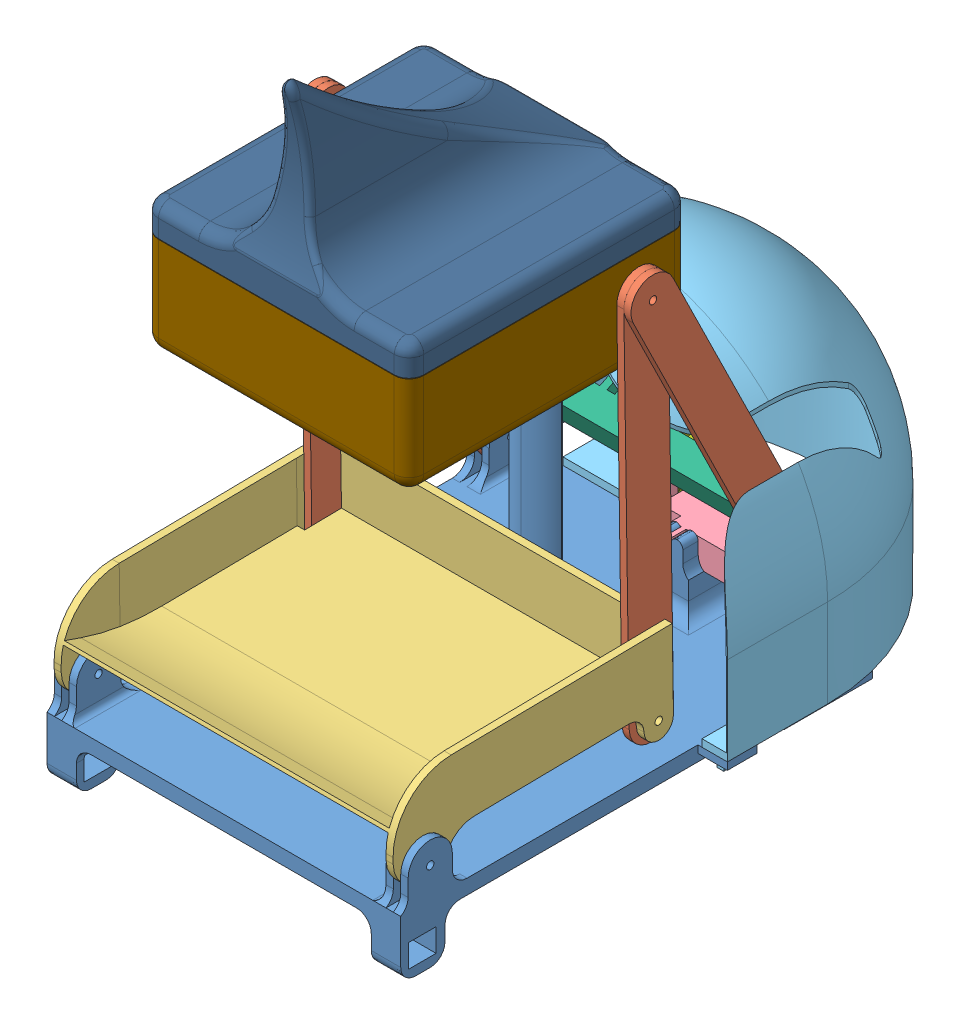
SolidWorks assembly Assembly, configuration Default. Lengths in mm.
Overall size (177.8 285.2 260.6).
13 component instances, 10 part files, 37 mates.
Components (placement in the parent):
- Base-1: Base [Default] at origin size (177.8 177.8 230.14)
- LinkGround-1: LinkGround [Follower] at (149.098 19.05 12.7) x (0 0.897199 0.441627) z (-1 0 0) size (196.85 19.05 3.05)
- ExtendedCrank-1: ExtendedCrank [Default] at (149.225 28.5357 89.033) x (-1 0 0) z (0 -0.015264 0.999884) size (146.05 40.64 120.65)
- LinkGround-3: LinkGround [Top] at (6.35 20.6008 88.9118) x (0 0.999893 0.014618) z (1 0 0) size (177.04 19.05 3.05)
- LinkGround-4: LinkGround [Top] at (143.002 178.5719 91.2213) x (0 -0.999893 -0.014618) z (1 0 0) size (177.04 19.05 3.05)
- LinkGround-8: LinkGround [Follower] at (6.35 19.05 12.7) x (0 0.897199 0.441627) z (-1 0 0) size (196.85 19.05 3.05)
- ServoMock-1: ServoMock [Default] at (115.57 32.4287 -6.1468) x (0 0 1) z (0 -1 0) size (42.32 37.85 19.81)
- Part2-1: Part2 [Default] at (0 6.35 0) x (1 0 0) z (0 1 0) size (177.8 139.57 134.62)
- NewServoHinge-1: NewServoHinge [Default] at (76.2 75.4719 46.7291) x (0 0.441627 -0.897199) z (1 0 0) size (30.48 12.7 145.8)
- ServoMountWheel-1: ServoMountWheel [Default] at (77.724 41.0778 -1.0841) x (0 -0.463784 0.885949) z (-1 0 0) size (50.53 31.75 8.57)
- LinkServo-1: LinkServo [Default] at (74.5236 47.7816 -6.8208) x (0 0.76136 0.64833) z (0 0.64833 -0.76136) size (56.17 3.17 12.7)
- PiHolder-1: PiHolder [Default] at (0 158.75 0) x (1 0 0) z (0 1 0) size (114.3 120.65 43.18)
- Fin-2: Fin [Default] at (152.146 184.15 240.2942) x (-1 0 0) z (0 1 0) size (114.3 122.34 88.35)
Mates (geometry in assembly coordinates):
- Coincident1: coincident: plane of Base-1 through (146.05 0 203.2) normal (1 0 0); plane of LinkGround-1 through (146.05 19.05 12.7) normal (-1 0 0)
- Concentric1: concentric: cylinder of Base-1 through (142.875 19.05 12.7) axis (1 0 0) radius 1.5875; cylinder of LinkGround-1 through (146.05 19.05 12.7) axis (1 0 0) radius 1.5875
- Coincident3: coincident: plane of Base-1 through (3.175 0 0) normal (1 0 0); plane of ExtendedCrank-1 through (3.175 25.996 88.9942) normal (-1 0 0)
- Concentric3: concentric: cylinder of Base-1 through (9.525 19.05 190.5) axis (-1 0 0) radius 1.5875; cylinder of ExtendedCrank-1 through (149.225 19.05 190.5) axis (-1 0 0) radius 1.5875
- Coincident4: coincident: plane of ExtendedCrank-1 through (6.35 28.5357 89.033) normal (1 0 0); plane of LinkGround-3 through (6.35 20.6008 88.9118) normal (-1 0 0)
- Concentric4: concentric: cylinder of ExtendedCrank-1 through (6.35 20.6008 88.9118) axis (-1 0 0) radius 1.5875; cylinder of LinkGround-3 through (9.398 20.6008 88.9118) axis (-1 0 0) radius 1.5875
- Concentric6: concentric: cylinder of LinkGround-1 through (146.05 178.5719 91.2213) axis (1 0 0) radius 1.5875; cylinder of LinkGround-4 through (146.05 178.5719 91.2213) axis (-1 0 0) radius 1.5875
- Coincident5: coincident: plane of LinkGround-1 through (146.05 19.05 12.7) normal (-1 0 0); plane of LinkGround-4 through (146.05 178.5719 91.2213) normal (1 0 0)
- Concentric7: concentric: cylinder of ExtendedCrank-1 through (146.05 20.6008 88.9118) axis (1 0 0) radius 1.5875; cylinder of LinkGround-4 through (146.05 20.6008 88.9118) axis (-1 0 0) radius 1.5875
- Concentric10: concentric: cylinder of Base-1 through (9.525 19.05 12.7) axis (-1 0 0) radius 1.5875; cylinder of LinkGround-8 through (3.302 19.05 12.7) axis (1 0 0) radius 1.5875
- Concentric11: concentric: cylinder of LinkGround-3 through (9.398 178.5719 91.2213) axis (-1 0 0) radius 1.5875; cylinder of LinkGround-8 through (3.302 178.5719 91.2213) axis (1 0 0) radius 1.5875
- Coincident16: coincident: plane of LinkGround-3 through (6.35 20.6008 88.9118) normal (-1 0 0); plane of LinkGround-8 through (6.35 19.05 12.7) normal (1 0 0)
- Parallel5: parallel: plane of ServoMock-1 through (89.408 32.4287 -6.1468) normal (0 1 0); plane of assembly through (0 0 0) normal (0 1 0)
- InPlace1: in place: plane of Base-1 through (0 6.35 0) normal (0 1 0); plane of Part2-1 through (0 6.35 0) normal (0 1 0); moOrthogonalPlaneRef_w of Base-1 through (0 6.35 0) normal (0 1 0); plane of Part2-1 through (0 6.35 0) normal (0 0 -1); plane of Base-1 through (0 6.35 0) normal (0 1 0); plane of Part2-1 through (0 6.35 0) normal (1 0 0); plane of Base-1 through (0 6.35 0) normal (0 1 0); unknown of Part2-1
- Coincident20: coincident: plane of Base-1; plane of Part2-1
- Coincident21: coincident: moOrthogonalPlaneRef_w of Base-1 through (0 6.35 0) normal (0 0 -1); plane of Part2-1 through (0 6.35 0) normal (0 0 -1)
- Coincident22: coincident: moOrthogonalPlaneRef_w of Base-1 through (0 6.35 0) normal (-1 0 0); plane of Part2-1 through (0 6.35 0) normal (1 0 0)
- Coincident19: coincident: plane of LinkGround-8 through (3.302 19.05 12.7) normal (-1 0 0); plane of NewServoHinge-1 through (3.302 75.4719 46.7291) normal (-1 0 0)
- Coincident21: coincident: plane of LinkGround-8 through (6.35 80.5197 36.4741) normal (0 -0.897199 -0.441627); plane of NewServoHinge-1 through (3.302 75.4719 46.7291) normal (0 0.897199 0.441627)
- Coincident22: coincident: plane of LinkGround-8 through (6.35 80.5197 36.4741) normal (0 -0.441627 0.897199); plane of NewServoHinge-1 through (3.302 80.5197 36.4741) normal (0 0.441627 -0.897199)
- Coincident23: coincident: plane of LinkGround-8 through (3.302 19.05 12.7) normal (-1 0 0); plane of NewServoHinge-1 through (3.302 75.4719 46.7291) normal (-1 0 0)
- Coincident26: coincident: plane of ServoMock-1 through (77.724 26.4597 13.97) normal (-1 0 0); plane of ServoMountWheel-1 through (77.724 41.0778 -1.0841) normal (1 0 0)
- Concentric12: concentric: circle of ServoMock-1; cylinder of ServoMountWheel-1 through (78.994 26.4597 13.97) axis (-1 0 0) radius 1.5875
- Coincident28: coincident: plane of Base-1 through (0 33.1907 23.368) normal (0 0 -1); plane of ServoMock-1 through (89.408 32.4287 23.368) normal (0 0 1)
- Coincident29: coincident: plane of Base-1 through (0 20.4907 0) normal (0 1 0); plane of ServoMock-1 through (89.408 20.4907 -6.1468) normal (0 -1 0)
- Coincident30: coincident: plane of Base-1 through (93.4974 33.1907 0) normal (1 0 0); plane of ServoMock-1 through (93.4974 20.4907 -12.5476) normal (-1 0 0)
- Concentric13: concentric: cylinder of ServoMountWheel-1 through (72.009 47.7816 -6.8208) axis (1 0 0) radius 1.5875; cylinder of LinkServo-1 through (77.6986 47.7816 -6.8208) axis (-1 0 0) radius 1.5875
- Coincident31: coincident: plane of ServoMountWheel-1 through (74.5236 26.4597 13.97) normal (1 0 0); plane of LinkServo-1 through (74.5236 47.7816 -6.8208) normal (-1 0 0)
- Concentric14: concentric: cylinder of NewServoHinge-1 through (71.4375 80.8799 21.3638) axis (1 0 0) radius 1.5875; cylinder of LinkServo-1 through (77.6986 80.8799 21.3638) axis (-1 0 0) radius 1.5875
- Coincident32: coincident: plane of NewServoHinge-1 through (74.5236 79.9683 20.9151) normal (1 0 0); plane of LinkServo-1 through (74.5236 47.7816 -6.8208) normal (-1 0 0)
- InPlace2: in place: plane of Base-1 through (0 158.75 0) normal (0 1 0); plane of PiHolder-1 through (0 158.75 0) normal (0 1 0); plane of Base-1 through (0 158.75 0) normal (0 1 0); plane of PiHolder-1 through (0 158.75 0) normal (0 0 -1); plane of Base-1 through (0 158.75 0) normal (0 1 0); plane of PiHolder-1 through (0 158.75 0) normal (1 0 0); plane of Base-1 through (0 158.75 0) normal (0 1 0); unknown of PiHolder-1
- Coincident33: coincident: plane of Base-1; plane of PiHolder-1
- Coincident34: coincident: moOrthogonalPlaneRef_w of Base-1 through (0 158.75 0) normal (0 0 -1); plane of PiHolder-1 through (0 158.75 0) normal (0 0 -1)
- Coincident35: coincident: moOrthogonalPlaneRef_w of Base-1 through (0 158.75 0) normal (-1 0 0); plane of PiHolder-1 through (0 158.75 0) normal (1 0 0)
- Coincident38: coincident: plane of PiHolder-1 through (129.54 140.97 66.2991) normal (-1 0 0); plane of Fin-2 through (129.54 177.8 66.0451) normal (1 0 0)
- Coincident39: coincident: plane of PiHolder-1 through (19.05 140.97 176.7891) normal (0 0 -1); plane of Fin-2 through (126.746 177.8 176.7891) normal (0 0 1)
- Coincident40: coincident: plane of PiHolder-1 through (0 184.15 0) normal (0 1 0); plane of Fin-2 through (25.146 184.15 66.0451) normal (0 -1 0)
